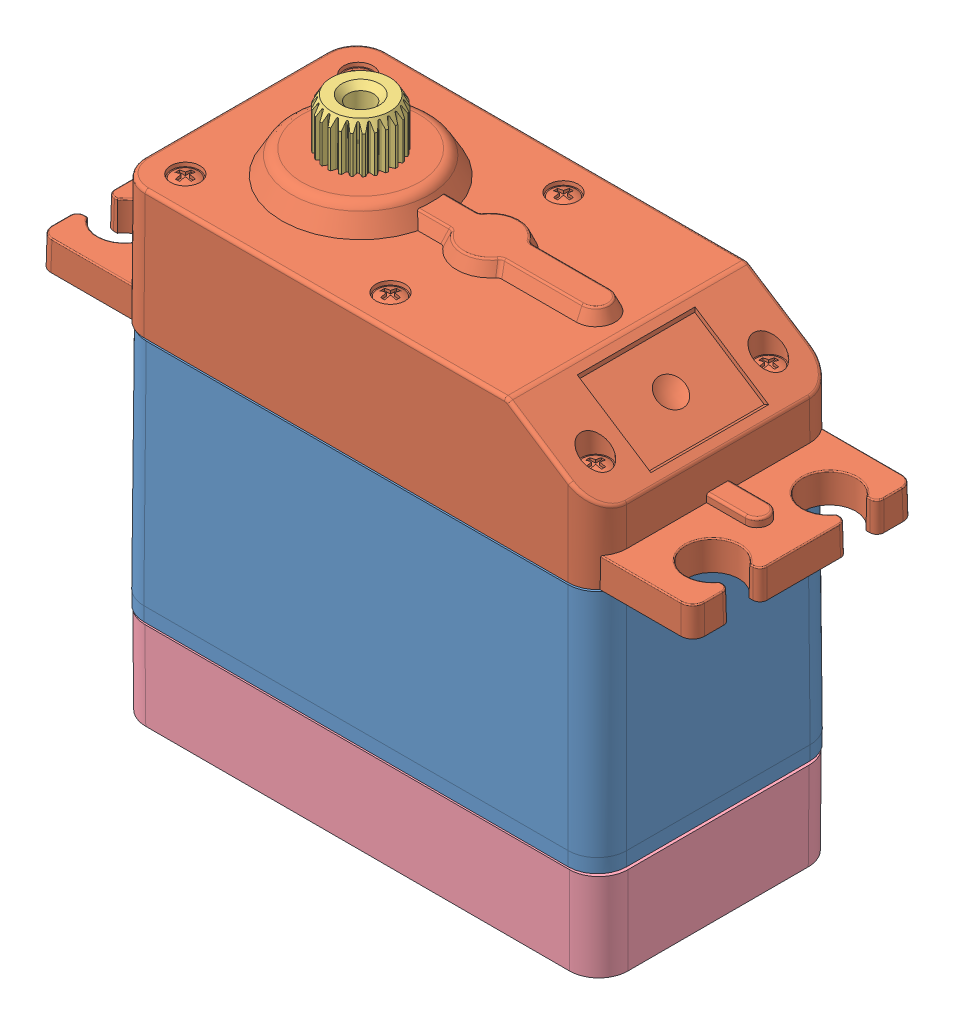
SolidWorks assembly SR431外观, configuration 默认. Lengths in mm.
Overall size (55.9 52.75 20.7).
6 component instances, 4 part files, 0 mates.
Components (placement in the parent):
- 431_ASM_21_ASM-1: 431_ASM_21_ASM [默认] at origin size (55.9 52.75 20.7)
  - MIDDLE-SHELL_2-1: MIDDLE-SHELL_2 [默认] at origin size (41.3 20.8 20.7)
  - UPPER-SHELL_2-1: UPPER-SHELL_2 [默认] at (0 19.85 0) size (55.9 12.95 20.7)
  - FIVE-STAGE-GEAR_ASM_1_ASM-1: FIVE-STAGE-GEAR_ASM_1_ASM [默认] at (-9.95 26.55 0) x (0 -1 0) z (-0.029666 0 0.99956) size (5 5.96 5.95)
    - FIVE-STAGE-GEAR_2-1: FIVE-STAGE-GEAR_2 [默认] x (0 0 -1) z (-1 0 0) size (5.95 5.96 5)
  - 430-431-HUO-GAI_4-1: 430-431-HUO-GAI_4 [默认] at (0 16.7 0) size (41.33 16.25 20.5)
